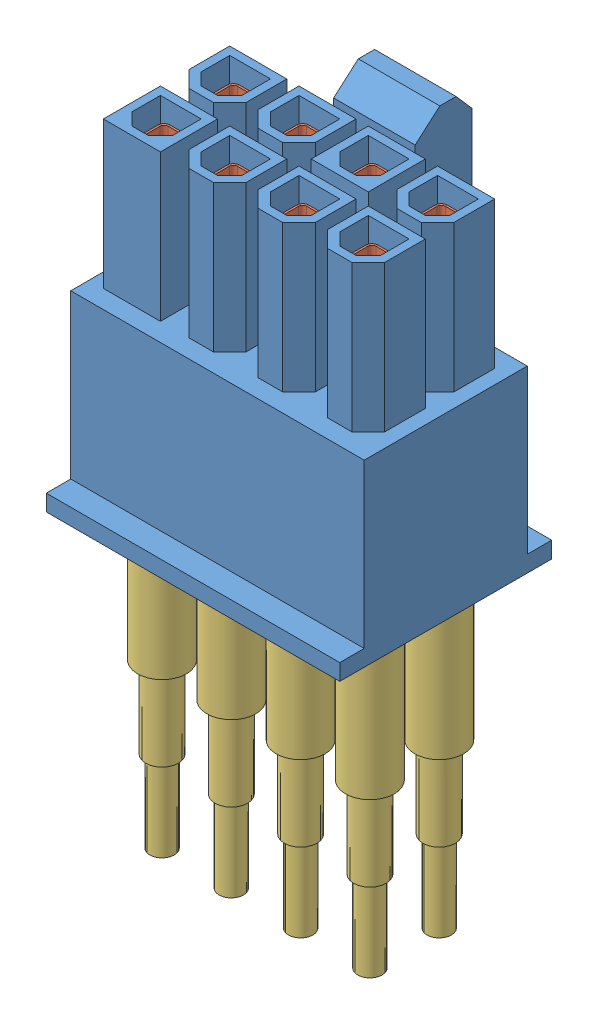
SolidWorks assembly ATX-12V-8-Pin, configuration Standard. Lengths in mm.
Overall size (18 39.77 15).
17 component instances, 3 part files, 6 mates.
Components (placement in the parent):
- ATX-12V-8-Pin-Body-1: ATX-12V-8-Pin-Body [Standard] at (-3.198 -9.0322 21) size (18 21 15)
- ATX-Main-24-Pin-crimp-1: ATX-Main-24-Pin-crimp [Standard] at (-9.573 0.693 19.9) x (0 1 0) z (-1 0 0) size (15.03 2.9 3.08)
- ATX-Main-24-Pin-crimp-2: ATX-Main-24-Pin-crimp [Standard] at (-9.573 0.693 24.15) x (0 1 0) z (-1 0 0) size (15.03 2.9 3.08)
- ATX-Main-24-Pin-crimp-3: ATX-Main-24-Pin-crimp [Standard] at (-5.323 0.693 19.9) x (0 1 0) z (-1 0 0) size (15.03 2.9 3.08)
- ATX-Main-24-Pin-crimp-4: ATX-Main-24-Pin-crimp [Standard] at (-5.323 0.693 24.15) x (0 1 0) z (-1 0 0) size (15.03 2.9 3.08)
- ATX-Main-24-Pin-crimp-5: ATX-Main-24-Pin-crimp [Standard] at (-1.073 0.693 19.9) x (0 1 0) z (-1 0 0) size (15.03 2.9 3.08)
- ATX-Main-24-Pin-crimp-6: ATX-Main-24-Pin-crimp [Standard] at (-1.073 0.693 24.15) x (0 1 0) z (-1 0 0) size (15.03 2.9 3.08)
- ATX-Main-24-Pin-crimp-7: ATX-Main-24-Pin-crimp [Standard] at (3.177 0.693 19.9) x (0 1 0) z (-1 0 0) size (15.03 2.9 3.08)
- ATX-Main-24-Pin-crimp-8: ATX-Main-24-Pin-crimp [Standard] at (3.177 0.693 24.15) x (0 1 0) z (-1 0 0) size (15.03 2.9 3.08)
- Kabelstueck-750µm-1: Kabelstueck-750µm [Standard] at (-9.573 -2.807 18.775) x (0 0 -1) z (-1 0 0) size (3 28 3)
- Kabelstueck-750µm-2: Kabelstueck-750µm [Standard] at (-9.573 -2.807 23.025) x (0 0 -1) z (-1 0 0) size (3 28 3)
- Kabelstueck-750µm-3: Kabelstueck-750µm [Standard] at (-5.323 -2.807 18.775) x (0 0 -1) z (-1 0 0) size (3 28 3)
- Kabelstueck-750µm-4: Kabelstueck-750µm [Standard] at (-5.323 -2.807 23.025) x (0 0 -1) z (-1 0 0) size (3 28 3)
- Kabelstueck-750µm-5: Kabelstueck-750µm [Standard] at (-1.073 -2.807 18.775) x (0 0 -1) z (-1 0 0) size (3 28 3)
- Kabelstueck-750µm-6: Kabelstueck-750µm [Standard] at (-1.073 -2.807 23.025) x (0 0 -1) z (-1 0 0) size (3 28 3)
- Kabelstueck-750µm-7: Kabelstueck-750µm [Standard] at (3.177 -2.807 18.775) x (0 0 -1) z (-1 0 0) size (3 28 3)
- Kabelstueck-750µm-8: Kabelstueck-750µm [Standard] at (3.177 -2.807 23.025) x (0 0 -1) z (-1 0 0) size (3 28 3)
Mates (geometry in assembly coordinates):
- Deckungsgleich1: coincident anti-aligned: plane of ATX-12V-8-Pin-Body-1 through (-3.198 0.9678 21) normal (0 -1 0); plane of ATX-Main-24-Pin-crimp-1 through (-10.598 0.9678 17) normal (0 1 0)
- Deckungsgleich2: coincident anti-aligned: plane of ATX-12V-8-Pin-Body-1 through (-11.448 0.9678 17) normal (0 0 1); plane of ATX-Main-24-Pin-crimp-1 through (-9.573 0.693 17) normal (0 0 -1)
- Abstand1: distance = 0.85 mm anti-aligned: plane of ATX-Main-24-Pin-crimp-1 through (-8.548 0.693 19.9) normal (1 0 0); plane of ATX-12V-8-Pin-Body-1 through (-7.698 0.9678 17) normal (-1 0 0)
- Deckungsgleich4: coincident anti-aligned: plane of ATX-Main-24-Pin-crimp-1 through (-10.073 -2.807 19.275) normal (0 -1 0); plane of Kabelstueck-750µm-1 through (-9.573 -2.807 18.775) normal (0 1 0)
- Tangential1: tangent anti-aligned: plane of ATX-Main-24-Pin-crimp-1 through (-9.573 0.693 19.775) normal (0 0 -1); cylinder of Kabelstueck-750µm-1 through (-9.573 -22.807 18.775) axis (0 1 0) radius 1
- Deckungsgleich5: coincident aligned: plane of ATX-Main-24-Pin-crimp-1 through (-9.573 0.693 19.9) normal (-1 0 0); plane of Kabelstueck-750µm-1 through (-9.573 -2.807 18.775) normal (-1 0 0)
